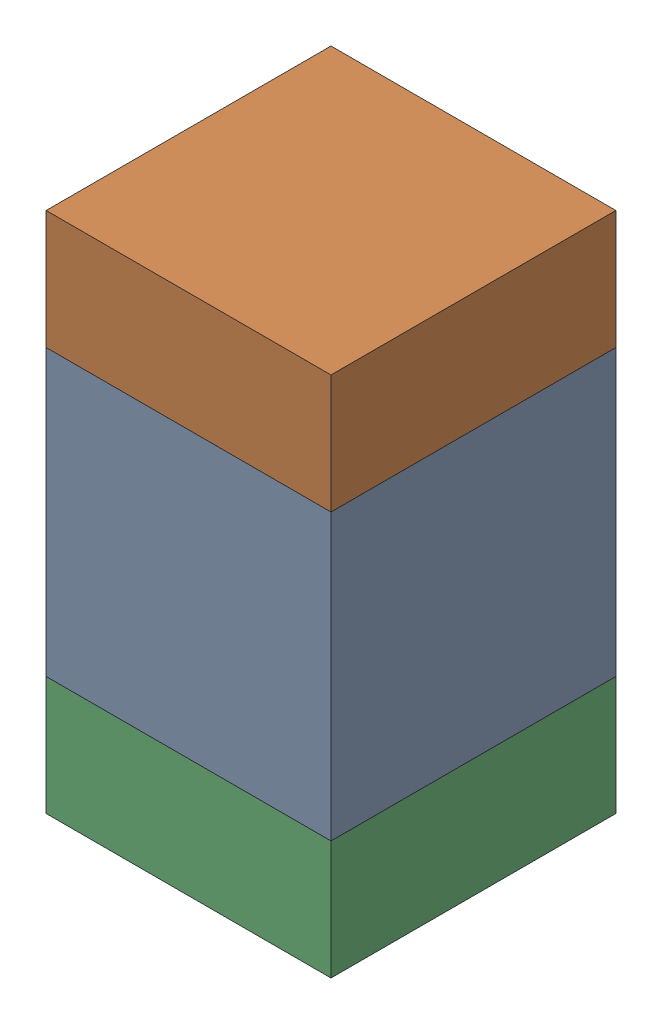
SolidWorks assembly C122_1PCB, configuration Default. Lengths in mm.
Overall size (0.6 1.1 0.6).
6 component instances, 2 part files, 0 mates.
Components (placement in the parent):
- 761606048-1: 761606048 [Default] at (106.5 121.7 0) size (0.6 0.6 0.6)
  - Extruded_9-1: Extruded_9 [Default] at origin size (0.6 0.6 0.6)
- 854785296-1: 854785296 [Default] at (106.5 122.125 0) size (0.6 0.25 0.6)
  - Extruded_10-1: Extruded_10 [Default] at origin size (0.6 0.25 0.6)
- 854785296-2: 854785296 [Default] at (106.5 121.275 0) size (0.6 0.25 0.6)
  - Extruded_10-1: Extruded_10 [Default] at origin size (0.6 0.25 0.6)
